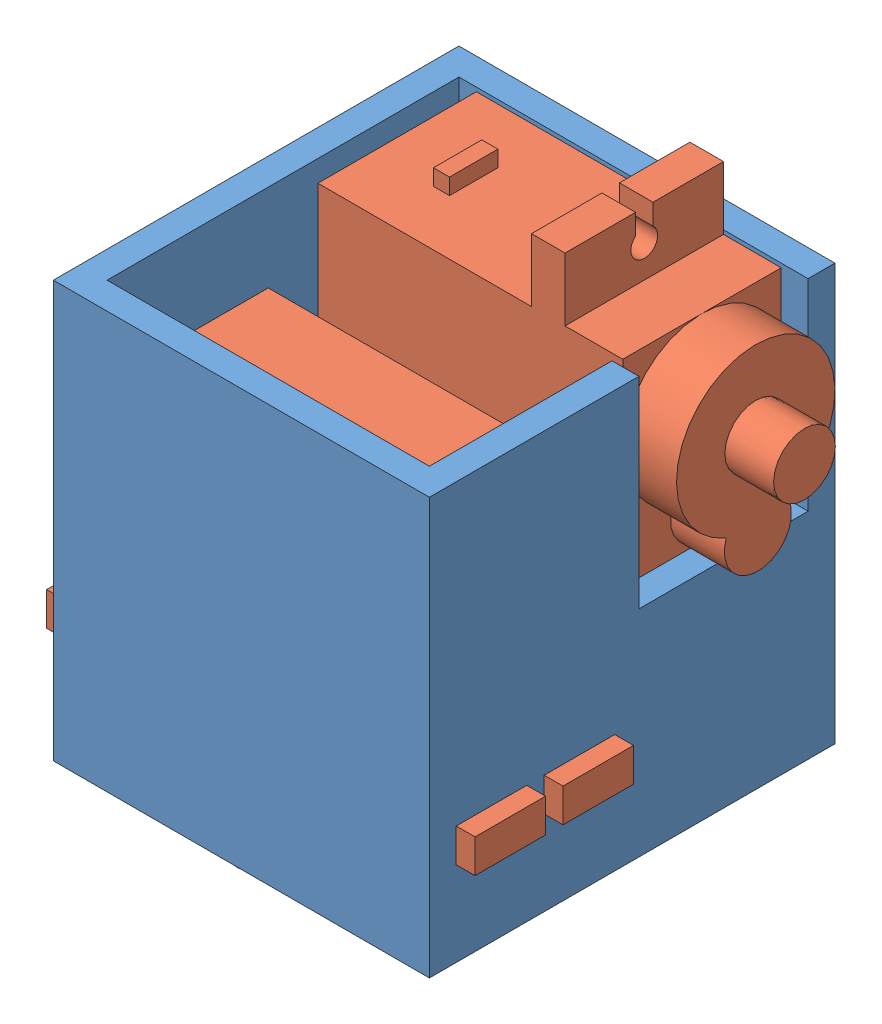
SolidWorks assembly Assemblage boitier, configuration Défaut. Lengths in mm.
Overall size (36.13 41.03 30.2).
3 component instances, 2 part files, 7 mates.
Components (placement in the parent):
- boite genoux-1: boite genoux [Défaut] at (-42.6329 -18.6805 -13.9) size (28 31 30.2)
- SG90_base-1: SG90_base [Défaut] at (-39.3329 -10.4805 -11.9) x (0 -1 0) z (0 0 1) size (31.9 30.33 11.8)
- SG90_base-2: SG90_base [Défaut] at (-17.9329 6.0195 14.3) x (1 0 0) z (0 0 -1) size (31.9 30.33 11.8)
Mates (geometry in assembly coordinates):
- Coïncidente1: coincident anti-aligned: plane of boite genoux-1 through (-42.6329 -18.6805 -11.9) normal (0 0 1); plane of SG90_base-1 through (-39.3329 -10.4805 -11.9) normal (0 0 -1)
- Coïncidente6: coincident anti-aligned: plane of boite genoux-1 through (-16.6329 -18.6805 16.3) normal (-1 0 0); plane of SG90_base-1 through (-16.6329 12.0195 -0.1) normal (1 0 0)
- Coïncidente7: coincident anti-aligned: plane of boite genoux-1 through (-42.6329 -15.1805 -13.9) normal (0 1 0); plane of SG90_base-1 through (-20.9329 -15.1805 -0.1) normal (0 -1 0)
- Coïncidente10: coincident anti-aligned: plane of SG90_base-1 through (-39.3329 -10.4805 -0.1) normal (0 0 1); plane of SG90_base-2 through (-17.9329 6.0195 -0.1) normal (0 0 -1)
- Coïncidente11: coincident: line of boite genoux-1 through (-25.6329 -16.6805 14.3) axis (0 0 -1); plane of SG90_base-2 through (-40.4329 -16.6805 -0.1) normal (0 -1 0)
- Distance1: distance = 0.2 mm: cylinder of SG90_base-2 through (-34.5329 -20.6805 8.4) axis (0 1 0) radius 5.9; plane of boite genoux-1 through (-40.6329 -18.6805 16.3) normal (1 0 0)
- Coïncidente12: coincident anti-aligned: plane of boite genoux-1 through (-42.6329 -18.6805 14.3) normal (0 0 -1); plane of SG90_base-2 through (-17.9329 6.0195 14.3) normal (0 0 1)
